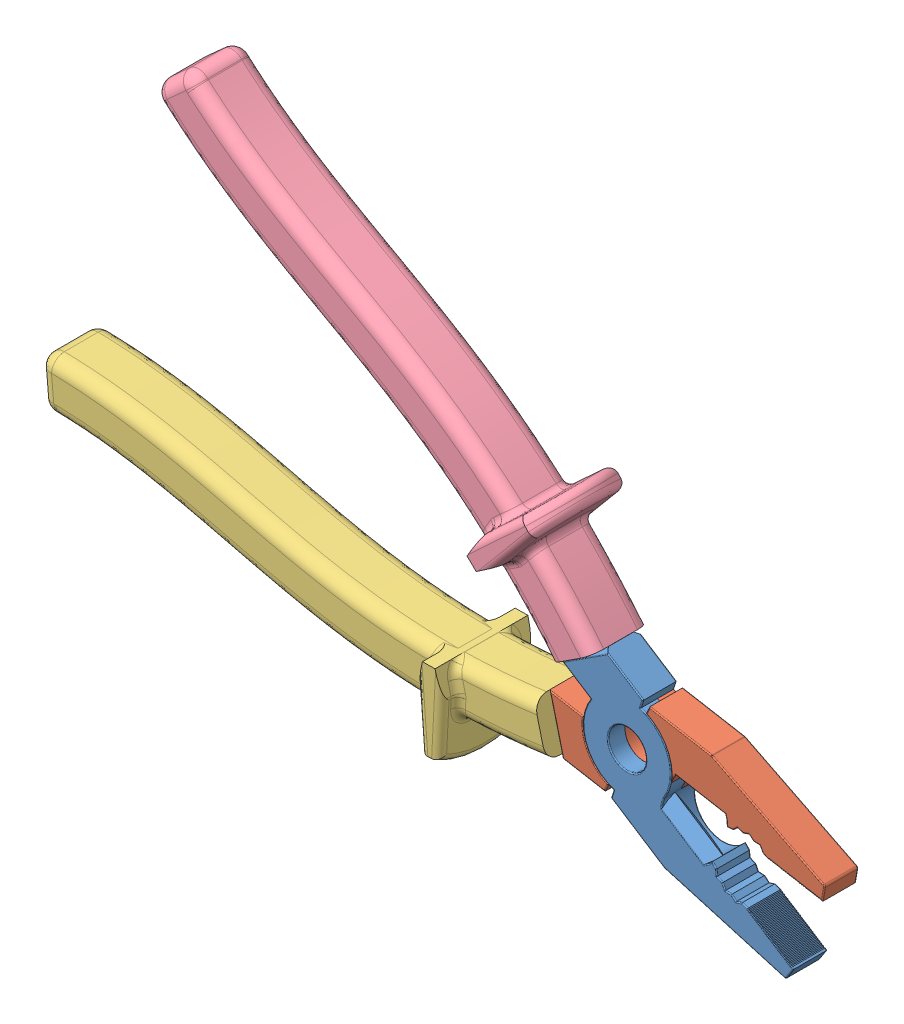
SolidWorks assembly Pliers, configuration Valor predeterminado. Lengths in mm.
Overall size (188.77 157.71 22.22).
4 component instances, 4 part files, 7 mates.
Components (placement in the parent):
- Peça1-1: Peça1 [Valor predeterminado] at (13.7717 10.1254 173.5827) x (-0.54174 -0.840546 0) z (0 0 1) size (32.84 181.5 8)
- Peça2-1: Peça2 [Valor predeterminado] at (20.552 27.4257 173.5827) x (-0.173648 -0.984808 0) z (0 0 1) size (32.84 181.5 8)
- Handle-1: Handle [Valor predeterminado] at (-43.3464 32.0576 169.5827) x (0.244423 -0.969669 0) z (0 0 1) size (58.08 112.5 22.22)
- Handle2-2: Handle2 [Valor predeterminado] at (-36.258 50.1439 169.5827) x (-0.838194 -0.545373 0) z (0 0 1) size (58.08 112.5 22.22)
Mates (geometry in assembly coordinates):
- Concêntrico2: concentric aligned: cylinder of Peça1-1 through (-25.734 35.5872 169.5827) axis (0 0 1) radius 4.5; cylinder of Peça2-1 through (-25.734 35.5872 165.5827) axis (0 0 1) radius 4.5
- Coincidente1: coincident anti-aligned: plane of Peça1-1 through (13.7717 10.1254 169.5827) normal (0 0 -1); plane of Peça2-1 through (-25.734 35.5872 169.5827) normal (0 0 1)
- ÂnguloLimite1: limit planar angle = 0.397972 rad anti-aligned: plane of Peça1-1 through (13.7717 10.1254 165.5827) normal (0.54174 0.840546 0); plane of Peça2-1 through (20.552 27.4257 165.5827) normal (-0.173648 -0.984808 0)
- Coincidente4: coincident aligned: line of Peça2-1 through (-44.1408 35.209 172.0827) axis (0.244423 -0.969669 0); line of Handle-1 through (-44.1408 35.209 172.0827) axis (0.244423 -0.969669 0)
- Coincidente5: coincident aligned: line of Peça2-1 through (-44.6296 37.1483 169.0827) axis (0 0 1); line of Handle-1 through (-44.6296 37.1483 169.0827) axis (0 0 1)
- Coincidente6: coincident aligned: line of Peça1-1 through (-38.9822 48.3715 172.0827) axis (0.838194 0.545373 0); line of Handle2-2 through (-38.9822 48.3715 172.0827) axis (0.838194 0.545373 0)
- Coincidente7: coincident aligned: line of Peça1-1 through (-40.6585 47.2807 169.0827) axis (0 0 1); line of Handle2-2 through (-40.6585 47.2807 169.0827) axis (0 0 1)
